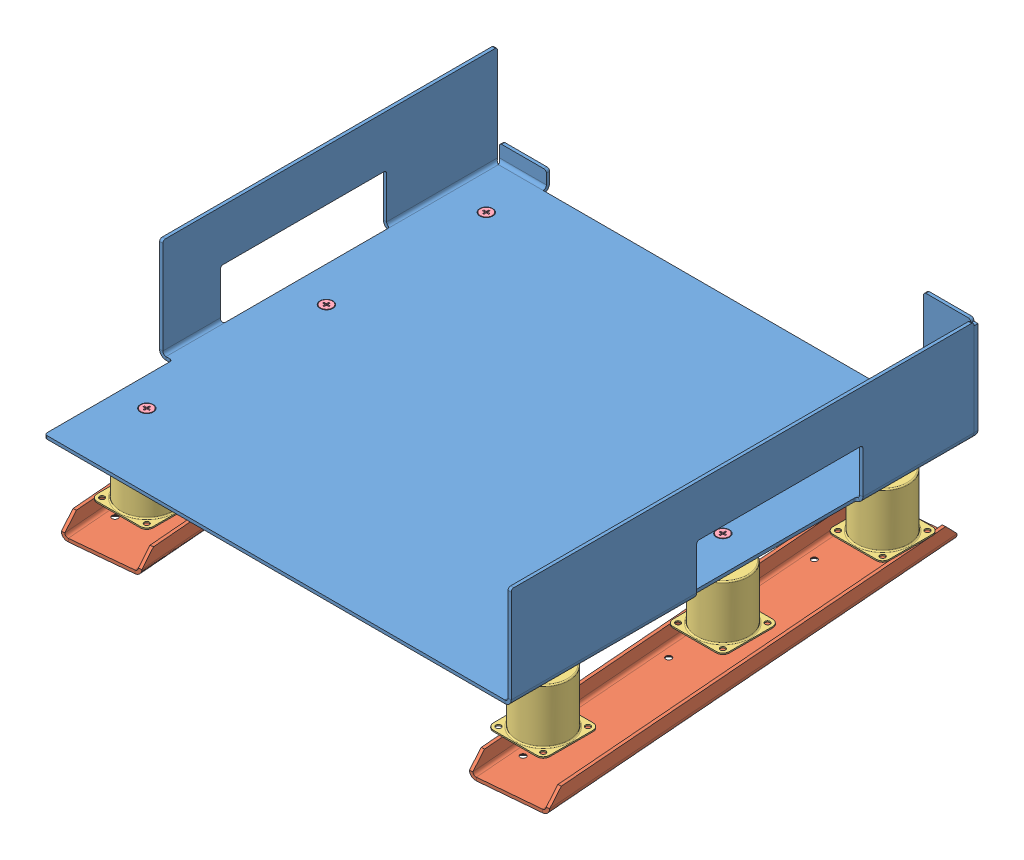
SolidWorks assembly Сборка, configuration По умолчанию. Lengths in mm.
Overall size (410.85 160.95 369.72).
15 component instances, 4 part files, 18 mates.
Components (placement in the parent):
- 1_Полка-1: 1_Полка [По умолчанию<Как обработанный>] at (-182.6691 43.1061 558.1681) size (375.45 80.44 365.44)
- 2_Основание-1: 2_Основание [По умолчанию] at (-162.1431 -35.9704 365.4512) x (-0.089698 -0.009696 -0.995922) z (0.995946 0.005963 -0.089758) size (350 15 58)
- 2_Основание-2: 2_Основание [По умолчанию] at (160.1624 -35.532 367.9834) x (0.085579 0.008259 0.996297) z (-0.996324 -0.003221 0.085608) size (350 15 58)
- 8_Амортизатор-1: 8_Амортизатор [По умолчанию] at (-150.1691 -17.3939 500.6681) size (44 59 44)
- 8_Амортизатор-2: 8_Амортизатор [По умолчанию] at (-150.1691 -17.3939 360.1991) size (44 59 44)
- 8_Амортизатор-3: 8_Амортизатор [По умолчанию] at (159.8309 -17.3939 360.1991) size (44 59 44)
- 8_Амортизатор-4: 8_Амортизатор [По умолчанию] at (159.8309 -17.3939 235.1991) size (44 59 44)
- 8_Амортизатор-5: 8_Амортизатор [По умолчанию] at (159.8309 -17.3939 500.6681) size (44 59 44)
- 8_Амортизатор-6: 8_Амортизатор [По умолчанию] at (-150.1691 -17.3939 235.1991) size (44 59 44)
- 7_Винт_М5-1: 7_Винт_М5 [По умолчанию] at (159.8309 31.2061 235.1991) size (9.3 12.3 9.3)
- 7_Винт_М5-2: 7_Винт_М5 [По умолчанию] at (159.8309 31.2061 500.6681) size (9.3 12.3 9.3)
- 7_Винт_М5-3: 7_Винт_М5 [По умолчанию] at (159.8309 31.2061 360.1991) size (9.3 12.3 9.3)
- 7_Винт_М5-4: 7_Винт_М5 [По умолчанию] at (-150.1691 31.2061 500.6681) size (9.3 12.3 9.3)
- 7_Винт_М5-5: 7_Винт_М5 [По умолчанию] at (-150.1691 31.2061 360.1991) size (9.3 12.3 9.3)
- 7_Винт_М5-6: 7_Винт_М5 [По умолчанию] at (-150.1691 31.2061 235.1991) size (9.3 12.3 9.3)
Mates (geometry in assembly coordinates):
- Концентричный1: concentric aligned: circle of 1_Полка-1; circle of 8_Амортизатор-6
- Совпадение2: coincident anti-aligned: plane of 1_Полка-1 through (-182.6691 40.6061 558.1681) normal (0 -1 0); plane of 8_Амортизатор-6 through (-150.1691 40.6061 235.1991) normal (0 1 0)
- Совпадение3: coincident aligned: cone of 1_Полка-1 through (-150.1691 40.7561 235.1991) axis (0 -1 0); cone of 7_Винт_М5-6 through (-150.1691 42.6561 235.1991) axis (0 -1 0)
- Концентричный2: concentric aligned: circle of 1_Полка-1; circle of 8_Амортизатор-2
- Совпадение4: coincident anti-aligned: plane of 1_Полка-1 through (-182.6691 40.6061 558.1681) normal (0 -1 0); plane of 8_Амортизатор-2 through (-150.1691 40.6061 360.1991) normal (0 1 0)
- Концентричный3: concentric aligned: circle of 1_Полка-1; circle of 8_Амортизатор-1
- Совпадение5: coincident anti-aligned: plane of 1_Полка-1 through (-182.6691 40.6061 558.1681) normal (0 -1 0); plane of 8_Амортизатор-1 through (-150.1691 40.6061 500.6681) normal (0 1 0)
- Концентричный4: concentric aligned: circle of 1_Полка-1; circle of 8_Амортизатор-4
- Совпадение6: coincident anti-aligned: plane of 1_Полка-1 through (-182.6691 40.6061 558.1681) normal (0 -1 0); plane of 8_Амортизатор-4 through (159.8309 40.6061 235.1991) normal (0 1 0)
- Концентричный5: concentric aligned: circle of 1_Полка-1; circle of 8_Амортизатор-3
- Совпадение7: coincident anti-aligned: plane of 1_Полка-1 through (-182.6691 40.6061 558.1681) normal (0 -1 0); plane of 8_Амортизатор-3 through (159.8309 40.6061 360.1991) normal (0 1 0)
- Концентричный6: concentric aligned: circle of 1_Полка-1; circle of 8_Амортизатор-5
- Совпадение8: coincident anti-aligned: plane of 1_Полка-1 through (-182.6691 40.6061 558.1681) normal (0 -1 0); plane of 8_Амортизатор-5 through (159.8309 40.6061 500.6681) normal (0 1 0)
- Совпадение9: coincident aligned: cone of 1_Полка-1 through (-150.1691 40.7561 360.1991) axis (0 -1 0); cone of 7_Винт_М5-5 through (-150.1691 42.6561 360.1991) axis (0 -1 0)
- Совпадение10: coincident aligned: cone of 1_Полка-1 through (-150.1691 40.7561 500.6681) axis (0 -1 0); cone of 7_Винт_М5-4 through (-150.1691 42.6561 500.6681) axis (0 -1 0)
- Совпадение11: coincident aligned: cone of 1_Полка-1 through (159.8309 40.7561 500.6681) axis (0 -1 0); cone of 7_Винт_М5-2 through (159.8309 42.6561 500.6681) axis (0 -1 0)
- Совпадение12: coincident aligned: cone of 1_Полка-1 through (159.8309 40.7561 360.1991) axis (0 -1 0); cone of 7_Винт_М5-3 through (159.8309 42.6561 360.1991) axis (0 -1 0)
- Совпадение14: coincident aligned: cone of 1_Полка-1 through (159.8309 40.7561 235.1991) axis (0 -1 0); cone of 7_Винт_М5-1 through (159.8309 42.6561 235.1991) axis (0 -1 0)
